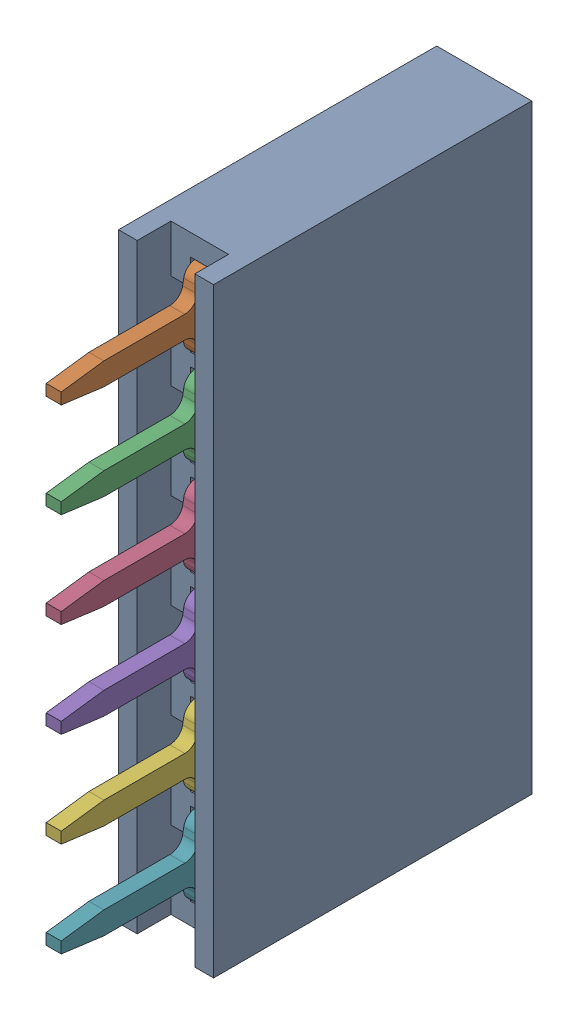
SolidWorks assembly H2_1.step, configuration Default. Lengths in mm.
Overall size (2.54 16.04 11.5).
8 component instances, 2 part files, 0 mates.
Components (placement in the parent):
- DS1023-1x6SF11_1.step-11: DS1023-1x6SF11_1.step [Default] at (501.645 334.5179 -1.647) x (0 -1 0) z (0 0 -1) size (16.04 2.54 11.5)
  - body_3.step-32: body_3.step [Default] at origin size (16.04 2.54 8.5)
  - contact_1.step-195: contact_1.step [Default] at origin size (2.3 0.4 9)
  - contact_1.step-196: contact_1.step [Default] at (2.54 0 0) size (2.3 0.4 9)
  - contact_1.step-199: contact_1.step [Default] at (5.08 0 0) size (2.3 0.4 9)
  - contact_1.step-200: contact_1.step [Default] at (7.62 0 0) size (2.3 0.4 9)
  - contact_1.step-201: contact_1.step [Default] at (10.16 0 0) size (2.3 0.4 9)
  - contact_1.step-202: contact_1.step [Default] at (12.7 0 0) size (2.3 0.4 9)
